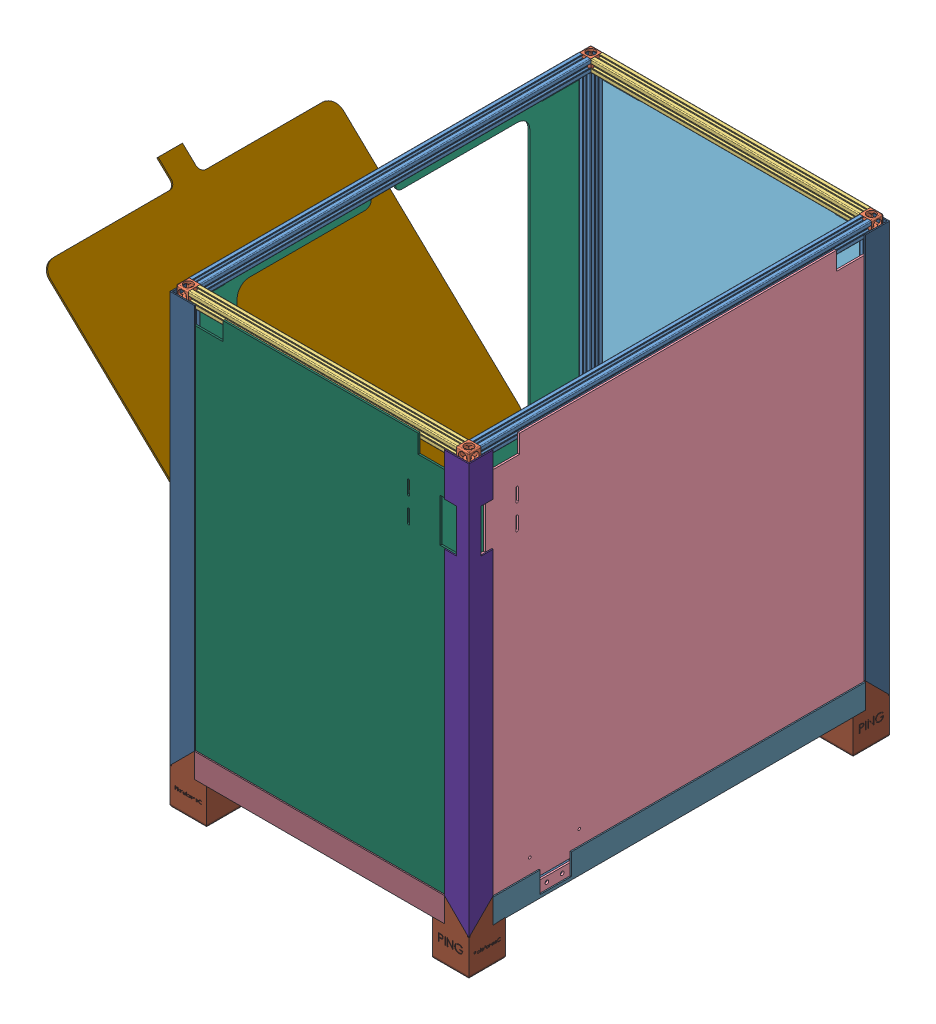
SolidWorks assembly carcasse, configuration Défaut. Lengths in mm.
Overall size (836.58 743 690).
62 component instances, 26 part files, 77 mates.
Components (placement in the parent):
- cadre-1: cadre [Défaut] at (-215.194 -19.8636 -400) size (480 20 680)
  - prof_20x20x600mm-1: prof_20x20x600mm [End Finishing_Non-Machined End Finish Options_Type_Single_] at (-14.8937 4.0689 600) size (20 20 640)
  - Blocks-1: Blocks [Défaut] at (-4.8937 14.0689 1240) x (0 1 0) z (0 0 1) size (20 20 20)
  - prof_20x20x600mm-3: prof_20x20x600mm [End Finishing_Non-Machined End Finish Options_Type_Single_] at (445.1063 4.0689 600) size (20 20 640)
  - Blocks-3: Blocks [Défaut] at (-4.8937 -5.9311 580) x (0 0 -1) z (0 1 0) size (20 20 20)
  - Blocks-4: Blocks [Défaut] at (435.1063 14.0689 600) x (0 1 0) z (0 0 -1) size (20 20 20)
  - Blocks-5: Blocks [Défaut] at (435.1063 -5.9311 1260) x (0 0 1) z (0 1 0) size (20 20 20)
  - prof_20x20x400mm-1: prof_20x20x400mm [End Finishing_Non-Machined End Finish Options_Type_Single_] at (435.1063 4.0689 590) x (0 0 1) z (-1 0 0) size (20 20 440)
  - prof_20x20x400mm-2: prof_20x20x400mm [End Finishing_Non-Machined End Finish Options_Type_Single_] at (435.1063 4.0689 1250) x (0 0 1) z (-1 0 0) size (20 20 440)
- prof_20x20x600mm-1: prof_20x20x600mm [End Finishing_Non-Machined End Finish Options_Type_Single_] at (229.9123 -25.7947 190) x (1 0 0) z (0 -1 0) size (20 20 640)
- prof_20x20x600mm-2: prof_20x20x600mm [End Finishing_Non-Machined End Finish Options_Type_Single_] at (229.9123 -25.7947 850) x (1 0 0) z (0 -1 0) size (20 20 640)
- prof_20x20x600mm-3: prof_20x20x600mm [End Finishing_Non-Machined End Finish Options_Type_Single_] at (-230.0877 -25.7947 850) x (1 0 0) z (0 -1 0) size (20 20 640)
- prof_20x20x600mm-4: prof_20x20x600mm [End Finishing_Non-Machined End Finish Options_Type_Single_] at (-230.0877 -25.7947 190) x (1 0 0) z (0 -1 0) size (20 20 640)
- cadre-2: cadre [Défaut] at (215.0186 -671.7258 -400) x (-1 0 0) z (0 0 1) size (480 20 680)
  - prof_20x20x600mm-1: prof_20x20x600mm [End Finishing_Non-Machined End Finish Options_Type_Single_] at (-14.8937 4.0689 600) size (20 20 640)
  - Blocks-1: Blocks [Défaut] at (-4.8937 14.0689 1240) x (0 1 0) z (0 0 1) size (20 20 20)
  - prof_20x20x600mm-3: prof_20x20x600mm [End Finishing_Non-Machined End Finish Options_Type_Single_] at (445.1063 4.0689 600) size (20 20 640)
  - Blocks-3: Blocks [Défaut] at (-4.8937 -5.9311 580) x (0 0 -1) z (0 1 0) size (20 20 20)
  - Blocks-4: Blocks [Défaut] at (435.1063 14.0689 600) x (0 1 0) z (0 0 -1) size (20 20 20)
  - Blocks-5: Blocks [Défaut] at (435.1063 -5.9311 1260) x (0 0 1) z (0 1 0) size (20 20 20)
  - prof_20x20x400mm-1: prof_20x20x400mm [End Finishing_Non-Machined End Finish Options_Type_Single_] at (435.1063 4.0689 590) x (0 0 1) z (-1 0 0) size (20 20 440)
  - prof_20x20x400mm-2: prof_20x20x400mm [End Finishing_Non-Machined End Finish Options_Type_Single_] at (435.1063 4.0689 1250) x (0 0 1) z (-1 0 0) size (20 20 440)
- plaque_acrylique_680x670-2: plaque_acrylique_680x670 [Défaut] at (239.9123 -350.7947 520) x (0 0 -1) z (1 0 0) size (680 670 3)
- plaque_acrylique_380x670_G-1: plaque_acrylique_380x670_G [Défaut] at (49.9123 -350.7947 177) size (480 670 3)
- plaque_acrylique_680x670_porte-1: plaque_acrylique_680x670_porte [Défaut] at (-243.0877 -350.7947 520) x (0 0 -1) z (1 0 0) size (680 670 3)
- charniere-1: charniere [Défaut] at (-236.7309 -495.7947 776.2875) x (0 0 1) z (0 -1 0) size (40 29.08 53.23)
  - axe charnière-1: axe charnière [Défaut] at (-76.2875 9.8568 0) size (40 5 5)
  - batant charnière-1: batant charnière [Défaut] at (-76.2875 10.1991 -17.6196) size (40 7 33.5)
  - batant charnière-2: batant charnière [Défaut] at (-36.2875 -2.6626 12.4029) x (-1 0 0) z (0 0.723942 -0.689861) size (40 7 33.5)
- charniere-2: charniere [Défaut] at (-236.7309 -495.7947 376.2875) x (0 0 1) z (0 -1 0) size (40 29.08 53.23)
  - axe charnière-1: axe charnière [Défaut] at (-76.2875 9.8568 0) size (40 5 5)
  - batant charnière-1: batant charnière [Défaut] at (-76.2875 10.1991 -17.6196) size (40 7 33.5)
  - batant charnière-2: batant charnière [Défaut] at (-36.2875 -2.6626 12.4029) x (-1 0 0) z (0 0.723942 -0.689861) size (40 7 33.5)
- porte-1: porte [Défaut] at (-349.1448 -393.231 520) x (0 0 -1) z (0.689861 0.723942 0) size (480 480 3)
- eclisse_40x40x670_bisote_x1-1: eclisse_40x40x670_bisote_x1 [Défaut] at (-225.0877 -688.7947 195.1136) size (40 673 40)
- eclisse_40x40x670_bisote_x1-2: eclisse_40x40x670_bisote_x1 [Défaut] at (-224.9741 -688.7947 845) x (0 0 -1) z (1 0 0) size (40 673 40)
- eclisse_40x40x670_bisote_x1-4: eclisse_40x40x670_bisote_x1 [Défaut] at (224.7986 -688.7947 195) x (0 0 1) z (-1 0 0) size (40 673 40)
- couvercle-1: couvercle [Défaut] at (451.7811 15.2953 693.3892) size (490 215 690) (hidden)
  - plaque_acrylique_680x210-2: plaque_acrylique_680x210 [Défaut] at (-694.8689 73.91 -173.3892) x (0 0 -1) z (1 0 0) size (680 210 3)
  - plaque_acrylique_380x210-2: plaque_acrylique_380x210 [Défaut] at (-401.8689 73.91 -516.3892) size (480 210 3)
  - plaque_acrylique_380x680-1: plaque_acrylique_380x680 [Défaut] at (-401.8689 178.91 -173.3892) x (1 0 0) z (0 1 0) size (480 680 3)
  - eclisse_40x40x404_bisote_x2-1: eclisse_40x40x404_bisote_x2 [Défaut] at (-206.8689 163.7964 -498.3892) x (0 0 1) z (0 -1 0) size (40 490 40)
  - eclisse_40x40x704_bisote_x2-1: eclisse_40x40x704_bisote_x2 [Défaut] at (-226.9825 163.91 -518.3892) x (0 -1 0) z (-1 0 0) size (40 690 40)
  - eclisse_40x40x404_bisote_x2-2: eclisse_40x40x404_bisote_x2 [Défaut] at (-696.8689 163.7964 151.6108) x (0 0 -1) z (0 -1 0) size (40 490 40)
  - eclisse_40x40x704_bisote_x2-2: eclisse_40x40x704_bisote_x2 [Défaut] at (-676.8689 163.7964 -518.3892) x (1 0 0) z (0 -1 0) size (40 690 40)
  - eclisse_40x40x222_bisote_x1-1: eclisse_40x40x222_bisote_x1 [Défaut] at (-676.7552 183.91 -498.3892) x (0 0 1) z (1 0 0) size (40 215 40)
  - eclisse_40x40x222_bisote_x1-2: eclisse_40x40x222_bisote_x1 [Défaut] at (-226.8689 183.91 -498.2755) x (-1 0 0) z (0 0 1) size (40 215 40)
  - eclisse_40x40x222_bisote_x1-4: eclisse_40x40x222_bisote_x1 [Défaut] at (-676.8689 183.91 151.4972) x (1 0 0) z (0 0 -1) size (40 215 40)
  - plaque_acrylique_380x210_Moteur-1: plaque_acrylique_380x210_Moteur [Défaut] at (-401.8689 73.91 166.6108) size (480 210 3)
  - plaque_acrylique_680x210_moteur-1: plaque_acrylique_680x210_moteur [Défaut] at (-211.8689 73.91 -173.3892) x (0 0 -1) z (1 0 0) size (680 210 3)
  - eclisse_40x40x222_bisote_x1_Moteur-1: eclisse_40x40x222_bisote_x1_Moteur [Défaut] at (-226.9825 183.91 151.6108) x (0 0 -1) z (-1 0 0) size (40 215 40)
- Pied-1: Pied [Défaut] at (184.9123 -688.7947 235) x (-1 0 0) z (0 -1 0) size (60 60 100)
- Pied-2: Pied [Défaut] at (184.9123 -688.7947 805) x (0 0 -1) z (0 -1 0) size (60 60 100)
- Pied-3: Pied [Défaut] at (-185.0877 -688.7947 805) x (1 0 0) z (0 -1 0) size (60 60 100)
- Pied-4: Pied [Défaut] at (-185.0877 -688.7947 235) x (0 0 1) z (0 -1 0) size (60 60 100)
- eclisse_bas_40x40x704-2: eclisse_bas_40x40x704 [Défaut] at (-225.0877 -670.681 825) x (1 0 0) z (0 1 0) size (40 610 40)
- eclisse_bas_40x40x404-1: eclisse_bas_40x40x404 [Défaut] at (-205.0877 -670.681 195) x (0 0 1) z (0 1 0) size (40 410 40)
- eclisse_bas_40x40x404-2: eclisse_bas_40x40x404 [Défaut] at (204.9123 -668.681 845) x (0 0 -1) z (0 1 0) size (40 410 40)
- eclisse_bas_support_Z_40x40x704-1: eclisse_bas_support_Z_40x40x704 [Défaut] at (224.7986 -670.7947 825) x (0 1 0) z (-1 0 0) size (40 610 40)
- plaque_acrylique_380x670_D-2: plaque_acrylique_380x670_D [Défaut] at (-50.0877 -350.7947 863) x (-1 0 0) z (0 0 -1) size (480 670 3)
- plaque_acrylique_bas_380x680-1: plaque_acrylique_bas_380x680 [Défaut] at (49.9123 -688.7947 520) x (1 0 0) z (0 1 0) size (480 680 3)
- eclisse_40x40x670_bisote_x1-Moteur-1: eclisse_40x40x670_bisote_x1-Moteur [Défaut] at (224.9123 -688.7947 844.8864) x (-1 0 0) z (0 0 -1) size (40 673 40)
Mates (geometry in assembly coordinates):
- Coïncidente50: coincident anti-aligned: plane of plaque_acrylique_680x670_porte-1 through (-243.0877 -350.7947 520) normal (-1 0 0); plane of charniere-1/batant charnière-1 through (-243.0877 -535.7947 740) normal (1 0 0)
- Coïncidente51: coincident anti-aligned: plane of plaque_acrylique_680x670_porte-1 through (-243.0877 -350.7947 520) normal (-1 0 0); plane of charniere-2/batant charnière-1 through (-243.0877 -535.7947 340) normal (1 0 0)
- Distance4: distance = 20 mm anti-aligned: plane of charniere-2/batant charnière-1 through (-246.5877 -495.7947 300) normal (0 0 -1); plane of plaque_acrylique_680x670_porte-1 through (-243.0877 -75.7947 280) normal (0 0 1)
- Coïncidente54: coincident aligned: line of plaque_acrylique_680x670_porte-1 through (-243.0877 -495.7947 740) axis (0 0 -1); line of charniere-2/batant charnière-1 through (-243.0877 -495.7947 340) axis (0 0 -1)
- Distance5: distance = 20 mm anti-aligned: plane of plaque_acrylique_680x670_porte-1 through (-243.0877 -75.7947 760) normal (0 0 -1); plane of charniere-1/batant charnière-1 through (-246.5877 -495.7947 740) normal (0 0 1)
- Coïncidente57: coincident aligned: line of plaque_acrylique_680x670_porte-1 through (-243.0877 -495.7947 740) axis (0 0 -1); line of charniere-1/batant charnière-1 through (-243.0877 -495.7947 740) axis (0 0 -1)
- Coïncidente62: coincident anti-aligned: plane of charniere-1/batant charnière-2 through (-273.1309 -465.6664 700) normal (0.689861 0.723942 0); plane of porte-1 through (-569.947 -182.8234 550) normal (-0.689861 -0.723942 0)
- Coïncidente63: coincident anti-aligned: line of charniere-1/batant charnière-2 through (-244.1732 -493.2609 720) axis (0 0 1); line of porte-1 through (-244.1732 -493.2609 740) axis (0 0 -1)
- Coïncidente64: coincident anti-aligned: plane of plaque_acrylique_680x670_porte-1 through (-243.0877 -75.7947 760) normal (0 0 -1); plane of porte-1 through (-546.1592 -201.3474 760) normal (0 0 1)
- Coïncidente66: coincident anti-aligned: plane of plaque_acrylique_680x670_porte-1 through (-243.0877 -350.7947 520) normal (-1 0 0); plane of eclisse_40x40x670_bisote_x1-1 through (-243.0877 -15.7947 177) normal (1 0 0)
- Coïncidente67: coincident aligned: plane of plaque_acrylique_680x670_porte-1 through (-240.0877 -15.7947 860) normal (0 1 0); plane of eclisse_40x40x670_bisote_x1-1 through (-225.0877 -15.7947 195.1136) normal (0 1 0)
- Coïncidente68: coincident anti-aligned: plane of plaque_acrylique_680x670-2 through (242.9123 -350.7947 520) normal (1 0 0); plane of eclisse_40x40x670_bisote_x1-4 through (242.9123 -15.7947 177) normal (-1 0 0)
- Coïncidente72: coincident anti-aligned: plane of plaque_acrylique_680x670_porte-1 through (-243.0877 -350.7947 520) normal (-1 0 0); plane of eclisse_40x40x670_bisote_x1-2 through (-243.0877 -15.7947 863) normal (1 0 0)
- Coïncidente100: coincident: plane of plaque_acrylique_680x670_porte-1 through (-240.0877 -15.7947 860) normal (0 1 0); line of eclisse_40x40x670_bisote_x1-2 through (-243.0877 -15.7947 863) axis (0 0 -1)
- Coïncidente130: coincident anti-aligned: plane of eclisse_40x40x670_bisote_x1-2 through (344.9123 -688.7947 865) normal (0 -0.707107 -0.707107); plane of Pied-3 through (-243.0877 -648.7947 825) normal (0 0.707107 0.707107)
- Coïncidente132: coincident anti-aligned: plane of plaque_acrylique_680x670_porte-1 through (-243.0877 -350.7947 520) normal (-1 0 0); plane of eclisse_bas_40x40x704-2 through (-243.0877 -688.7947 215) normal (1 0 0)
- Coïncidente134: coincident anti-aligned: line of eclisse_40x40x670_bisote_x1-2 through (-245.0877 -15.7947 825) axis (0 -1 0); line of eclisse_bas_40x40x704-2 through (-245.0877 -690.7947 825) axis (0 1 0)
- Coïncidente140: coincident anti-aligned: line of Pied-3 through (-205.0877 -648.7947 865) axis (0 -1 0); line of eclisse_bas_40x40x404-2 through (-205.0877 -688.7947 865) axis (0 1 0)
- Coïncidente142: coincident anti-aligned: plane of plaque_acrylique_680x670-2 through (242.9123 -350.7947 520) normal (1 0 0); plane of eclisse_bas_support_Z_40x40x704-1 through (242.9123 -688.7947 215) normal (-1 0 0)
- Coïncidente144: coincident anti-aligned: plane of Pied-2 through (242.9123 -648.7947 825) normal (0 0 -1); plane of eclisse_bas_support_Z_40x40x704-1 through (224.7986 -670.7947 825) normal (0 0 1)
- Coïncidente151: coincident anti-aligned: plane of Pied-3 through (-185.0877 -688.7947 805) normal (0 1 0); plane of eclisse_bas_40x40x404-2 through (-205.0877 -688.7947 865) normal (0 -1 0)
- Coïncidente156: coincident anti-aligned: plane of eclisse_bas_40x40x404-2 through (-205.0877 -686.7947 863) normal (0 0 -1); plane of plaque_acrylique_380x670_D-2 through (-50.0877 -350.7947 863) normal (0 0 1)
- Coïncidente157: coincident anti-aligned: plane of eclisse_40x40x670_bisote_x1-2 through (-243.0877 -15.7947 863) normal (0 0 -1); plane of plaque_acrylique_380x670_D-2 through (-50.0877 -350.7947 863) normal (0 0 1)
- Coïncidente163: coincident anti-aligned: plane of cadre-1/Blocks-1 through (-240.0877 -25.7947 860) normal (0 -1 0); plane of prof_20x20x600mm-3 through (-238.5877 -25.7947 858.5) normal (0 1 0)
- Coïncidente164: coincident aligned: plane of cadre-1/Blocks-1 through (-240.0877 -25.7947 860) normal (-1 0 0); plane of prof_20x20x600mm-3 through (-240.0877 -665.7947 853.75) normal (-1 0 0)
- Coïncidente165: coincident aligned: plane of cadre-1/Blocks-1 through (-220.0877 -5.7947 860) normal (0 0 1); plane of prof_20x20x600mm-3 through (-233.8377 -665.7947 860) normal (0 0 1)
- Coïncidente166: coincident anti-aligned: plane of prof_20x20x600mm-3 through (-238.5877 -665.7947 858.5) normal (0 -1 0); plane of cadre-2/Blocks-5 through (-220.0877 -665.7947 860) normal (0 1 0)
- Coïncidente167: coincident aligned: plane of prof_20x20x600mm-3 through (-233.8377 -665.7947 860) normal (0 0 1); plane of cadre-2/Blocks-5 through (-240.0877 -685.7947 860) normal (0 0 1)
- Coïncidente168: coincident aligned: plane of prof_20x20x600mm-3 through (-240.0877 -665.7947 853.75) normal (-1 0 0); plane of cadre-2/Blocks-5 through (-240.0877 -685.7947 840) normal (-1 0 0)
- Coïncidente169: coincident anti-aligned: plane of prof_20x20x600mm-2 through (221.4123 -665.7947 858.5) normal (0 -1 0); plane of cadre-2/Blocks-1 through (239.9123 -665.7947 860) normal (0 1 0)
- Coïncidente170: coincident aligned: plane of prof_20x20x600mm-2 through (226.1623 -665.7947 860) normal (0 0 1); plane of cadre-2/Blocks-1 through (219.9123 -685.7947 860) normal (0 0 1)
- Coïncidente171: coincident aligned: plane of prof_20x20x600mm-2 through (239.9123 -665.7947 853.75) normal (1 0 0); plane of cadre-2/Blocks-1 through (239.9123 -665.7947 860) normal (1 0 0)
- Coïncidente172: coincident anti-aligned: plane of prof_20x20x600mm-1 through (221.4123 -665.7947 198.5) normal (0 -1 0); plane of cadre-2/Blocks-3 through (219.9123 -665.7947 180) normal (0 1 0)
- Coïncidente173: coincident aligned: plane of prof_20x20x600mm-1 through (239.9123 -665.7947 193.75) normal (1 0 0); plane of cadre-2/Blocks-3 through (239.9123 -685.7947 200) normal (1 0 0)
- Coïncidente174: coincident aligned: plane of prof_20x20x600mm-1 through (233.6623 -665.7947 180) normal (0 0 -1); plane of cadre-2/Blocks-3 through (239.9123 -685.7947 180) normal (0 0 -1)
- Coïncidente175: coincident aligned: plane of cadre-1/Blocks-3 through (-240.0877 -5.7947 200) normal (-1 0 0); plane of prof_20x20x600mm-4 through (-240.0877 -665.7947 186.25) normal (-1 0 0)
- Coïncidente176: coincident aligned: plane of cadre-1/Blocks-3 through (-240.0877 -5.7947 180) normal (0 0 -1); plane of prof_20x20x600mm-4 through (-233.8377 -665.7947 180) normal (0 0 -1)
- Coïncidente177: coincident anti-aligned: plane of cadre-1/Blocks-3 through (-220.0877 -25.7947 180) normal (0 -1 0); plane of prof_20x20x600mm-4 through (-238.5877 -25.7947 198.5) normal (0 1 0)
- Coïncidente183: coincident aligned: plane of prof_20x20x600mm-2 through (239.9123 -665.7947 853.75) normal (1 0 0); plane of plaque_acrylique_380x670_D-2 through (239.9123 -15.7947 860) normal (1 0 0)
- Coïncidente185: coincident anti-aligned: plane of cadre-1/prof_20x20x600mm-3 through (239.9123 -12.0447 840) normal (1 0 0); plane of plaque_acrylique_680x670-2 through (239.9123 -350.7947 520) normal (-1 0 0)
- Coïncidente186: coincident aligned: plane of cadre-1/prof_20x20x400mm-2 through (-220.0877 -12.0447 860) normal (0 0 1); plane of plaque_acrylique_680x670-2 through (242.9123 -15.7947 860) normal (0 0 1)
- Coïncidente187: coincident aligned: plane of cadre-1/prof_20x20x400mm-1 through (-220.0877 -19.5447 180) normal (0 0 -1); plane of plaque_acrylique_680x670_porte-1 through (-240.0877 -15.7947 180) normal (0 0 -1)
- Coïncidente191: coincident anti-aligned: plane of cadre-2/prof_20x20x400mm-1 through (219.9123 -685.7947 193.75) normal (0 -1 0); plane of plaque_acrylique_bas_380x680-1 through (49.9123 -685.7947 520) normal (0 1 0)
- Coïncidente192: coincident aligned: plane of cadre-2/prof_20x20x400mm-2 through (219.9123 -679.5447 860) normal (0 0 1); plane of plaque_acrylique_bas_380x680-1 through (-240.0877 -685.7947 860) normal (0 0 1)
- Coïncidente193: coincident aligned: plane of cadre-2/prof_20x20x600mm-1 through (239.9123 -679.5447 840) normal (1 0 0); plane of plaque_acrylique_bas_380x680-1 through (239.9123 -685.7947 180) normal (1 0 0)
- Coïncidente195: coincident anti-aligned: plane of Pied-2 through (184.9123 -688.7947 805) normal (0 1 0); plane of plaque_acrylique_bas_380x680-1 through (49.9123 -688.7947 520) normal (0 -1 0)
- Coïncidente198: coincident anti-aligned: plane of Pied-1 through (184.9123 -688.7947 235) normal (0 1 0); plane of plaque_acrylique_bas_380x680-1 through (49.9123 -688.7947 520) normal (0 -1 0)
- Coïncidente199: coincident anti-aligned: line of eclisse_40x40x670_bisote_x1-4 through (244.9123 -688.7947 175) axis (0 0.707107 0.707107); line of Pied-1 through (244.9123 -648.7947 215) axis (0 -0.707107 -0.707107)
- Coïncidente200: coincident anti-aligned: plane of Pied-2 through (184.9123 -688.7947 805) normal (0 1 0); plane of plaque_acrylique_bas_380x680-1 through (49.9123 -688.7947 520) normal (0 -1 0)
- Coïncidente201: coincident anti-aligned: plane of plaque_acrylique_680x670-2 through (242.9123 -350.7947 520) normal (1 0 0); plane of Pied-2 through (242.9123 -648.7947 863) normal (-1 0 0)
- Coïncidente203: coincident aligned: plane of cadre-2/prof_20x20x600mm-3 through (-233.8377 -685.7947 840) normal (0 -1 0); plane of plaque_acrylique_680x670_porte-1 through (-240.0877 -685.7947 860) normal (0 -1 0)
- Coïncidente204: coincident anti-aligned: plane of prof_20x20x600mm-1 through (233.6623 -665.7947 180) normal (0 0 -1); plane of plaque_acrylique_380x670_G-1 through (49.9123 -350.7947 180) normal (0 0 1)
- Coïncidente205: coincident aligned: plane of cadre-2/prof_20x20x400mm-1 through (219.9123 -685.7947 186.25) normal (0 -1 0); plane of plaque_acrylique_380x670_G-1 through (-240.0877 -685.7947 180) normal (0 -1 0)
- Coïncidente206: coincident aligned: plane of prof_20x20x600mm-1 through (239.9123 -665.7947 186.25) normal (1 0 0); plane of plaque_acrylique_380x670_G-1 through (239.9123 -15.7947 180) normal (1 0 0)
- Coïncidente207: coincident anti-aligned: plane of prof_20x20x600mm-4 through (-240.0877 -665.7947 186.25) normal (-1 0 0); plane of plaque_acrylique_680x670_porte-1 through (-240.0877 -350.7947 520) normal (1 0 0)
- Coïncidente208: coincident anti-aligned: plane of plaque_acrylique_380x670_G-1 through (49.9123 -350.7947 177) normal (0 0 -1); plane of eclisse_40x40x670_bisote_x1-1 through (-243.0877 -15.7947 177) normal (0 0 1)
- Coïncidente210: coincident anti-aligned: plane of plaque_acrylique_380x670_G-1 through (49.9123 -350.7947 177) normal (0 0 -1); plane of eclisse_40x40x670_bisote_x1-4 through (242.9123 -15.7947 177) normal (0 0 1)
- Coïncidente211: coincident anti-aligned: plane of Pied-4 through (-185.0877 -688.7947 235) normal (0 1 0); plane of plaque_acrylique_bas_380x680-1 through (49.9123 -688.7947 520) normal (0 -1 0)
- Parallèle4: parallel anti-aligned: line of eclisse_40x40x670_bisote_x1-1 through (-245.0877 -688.7947 175) axis (0.707107 0.707107 0); line of Pied-4 through (-205.0877 -648.7947 175) axis (-0.707107 -0.707107 0)
- Coïncidente217: coincident aligned: plane of cadre-2/prof_20x20x600mm-1 through (233.6623 -685.7947 840) normal (0 -1 0); plane of plaque_acrylique_680x670-2 through (242.9123 -685.7947 860) normal (0 -1 0)
- Coïncidente218: coincident: plane of cadre-2/prof_20x20x400mm-2 through (219.9123 -685.7947 853.75) normal (0 -1 0); line of plaque_acrylique_380x670_D-2 through (239.9123 -685.7947 863) axis (-1 0 0)
- Coïncidente223: coincident anti-aligned: plane of eclisse_bas_support_Z_40x40x704-1 through (242.9123 -688.7947 215) normal (0 1 0); plane of plaque_acrylique_bas_380x680-1 through (49.9123 -688.7947 520) normal (0 -1 0)
- Coïncidente224: coincident anti-aligned: plane of eclisse_bas_40x40x704-2 through (-243.0877 -688.7947 215) normal (0 1 0); plane of plaque_acrylique_bas_380x680-1 through (49.9123 -688.7947 520) normal (0 -1 0)
- Coïncidente225: coincident anti-aligned: plane of plaque_acrylique_380x670_G-1 through (49.9123 -350.7947 177) normal (0 0 -1); plane of eclisse_bas_40x40x404-1 through (204.9123 -688.7947 177) normal (0 0 1)
- Coïncidente226: coincident anti-aligned: plane of eclisse_bas_40x40x404-1 through (204.9123 -688.7947 177) normal (0 1 0); plane of plaque_acrylique_bas_380x680-1 through (49.9123 -688.7947 520) normal (0 -1 0)
- Coïncidente227: coincident anti-aligned: plane of Pied-1 through (204.9123 -648.7947 177) normal (-1 0 0); plane of eclisse_bas_40x40x404-1 through (204.9123 -670.681 195) normal (1 0 0)
- Coïncidente228: coincident anti-aligned: plane of plaque_acrylique_680x670_porte-1 through (-243.0877 -350.7947 520) normal (-1 0 0); plane of Pied-3 through (-243.0877 -648.7947 825) normal (1 0 0)
- Coïncidente229: coincident anti-aligned: plane of plaque_acrylique_380x670_G-1 through (49.9123 -350.7947 177) normal (0 0 -1); plane of Pied-4 through (-205.0877 -648.7947 177) normal (0 0 1)
- Coïncidente230: coincident anti-aligned: plane of plaque_acrylique_680x670_porte-1 through (-243.0877 -350.7947 520) normal (-1 0 0); plane of Pied-4 through (-243.0877 -648.7947 177) normal (1 0 0)
- Coïncidente231: coincident anti-aligned: plane of plaque_acrylique_380x670_G-1 through (49.9123 -350.7947 177) normal (0 0 -1); plane of Pied-1 through (242.9123 -648.7947 177) normal (0 0 1)
- Coïncidente232: coincident aligned: plane of plaque_acrylique_380x670_G-1 through (49.9123 -350.7947 177) normal (0 0 -1); plane of couvercle-1/plaque_acrylique_380x210-2 through (49.9123 89.2053 177) normal (0 0 -1)
- Coïncidente233: coincident aligned: plane of couvercle-1/plaque_acrylique_380x210_Moteur-1 through (49.9123 89.2053 863) normal (0 0 1); plane of plaque_acrylique_380x670_D-2 through (-50.0877 -350.7947 863) normal (0 0 1)
- Coïncidente234: coincident anti-aligned: line of plaque_acrylique_680x670-2 through (242.9123 -15.7947 260) axis (0 0 1); line of couvercle-1/plaque_acrylique_680x210_moteur-1 through (242.9123 -15.7947 780) axis (0 0 -1)
- Coïncidente235: coincident aligned: plane of plaque_acrylique_680x670-2 through (242.9123 -350.7947 520) normal (1 0 0); plane of couvercle-1/plaque_acrylique_680x210_moteur-1 through (242.9123 89.2053 520) normal (1 0 0)
- Coïncidente236: coincident anti-aligned: plane of plaque_acrylique_680x670-2 through (242.9123 -350.7947 520) normal (1 0 0); plane of eclisse_40x40x670_bisote_x1-Moteur-1 through (242.9123 -15.7947 863) normal (-1 0 0)
- Coïncidente237: coincident anti-aligned: plane of plaque_acrylique_380x670_D-2 through (-50.0877 -350.7947 863) normal (0 0 1); plane of eclisse_40x40x670_bisote_x1-Moteur-1 through (242.9123 -15.7947 863) normal (0 0 -1)
- Coïncidente238: coincident anti-aligned: line of Pied-2 through (204.9123 -648.7947 865) axis (0.707107 -0.707107 0); line of eclisse_40x40x670_bisote_x1-Moteur-1 through (244.9123 -688.7947 865) axis (-0.707107 0.707107 0)
